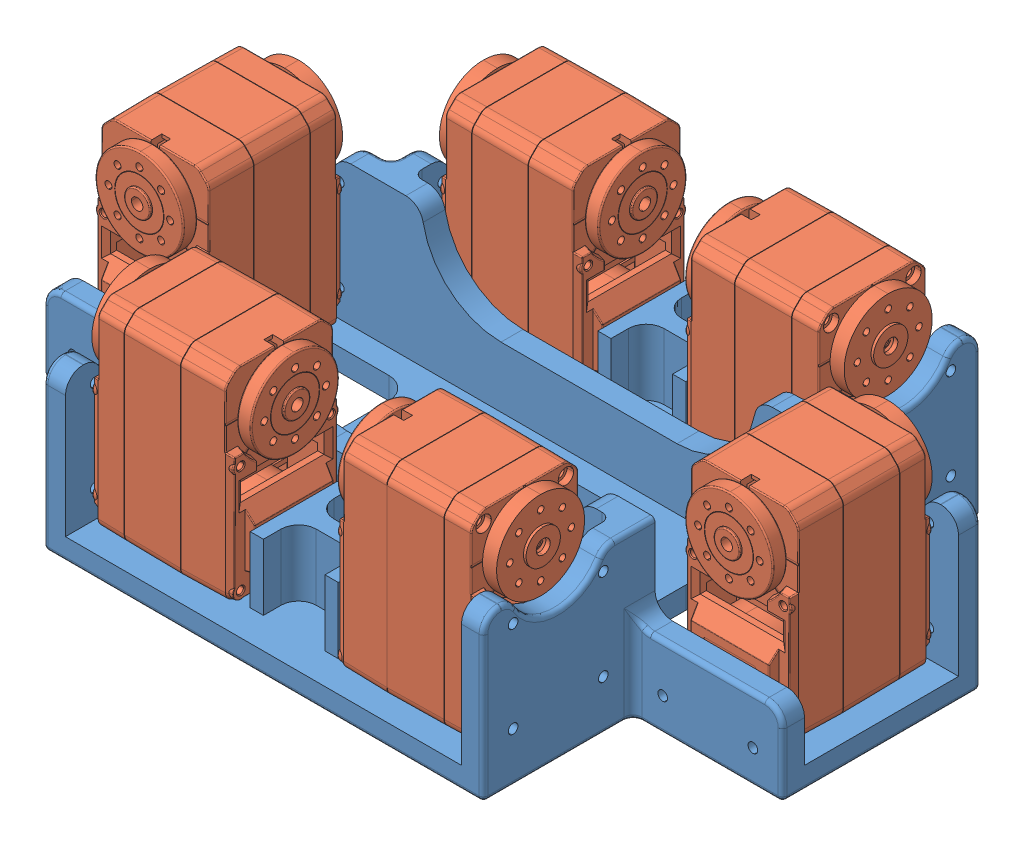
SolidWorks assembly Assem1, configuration Default. Lengths in mm.
Overall size (168 59.68 113).
8 component instances, 2 part files, 0 mates.
Components (placement in the parent):
- link0-1: link0 [Default] at origin size (168 59.68 113)
  - platform-v4-1: platform-v4 [Default] at (0 36.8 -17.5) x (-1 0 0) z (0 0 1) size (168 36.8 113)
  - Servo-LX-16A-1: Servo-LX-16A [Default] at (37.5 14.825 39.5) x (0 -1 0) z (0 0 1) size (54.66 37.3 26.46)
  - Servo-LX-16A-2: Servo-LX-16A [Default] at (-37.5 14.825 39.5) x (0 -1 0) z (0 0 -1) size (54.66 37.3 26.46)
  - Servo-LX-16A-3: Servo-LX-16A [Default] at (-67 14.825 -10) x (0 -1 0) z (1 0 0) size (54.66 37.3 26.46)
  - Servo-LX-16A-4: Servo-LX-16A [Default] at (-37.5 14.825 -39.5) x (0 -1 0) z (0 0 -1) size (54.66 37.3 26.46)
  - Servo-LX-16A-5: Servo-LX-16A [Default] at (37.5 14.825 -39.5) x (0 -1 0) z (0 0 1) size (54.66 37.3 26.46)
  - Servo-LX-16A-6: Servo-LX-16A [Default] at (67 14.825 -10) x (0 -1 0) z (1 0 0) size (54.66 37.3 26.46)
